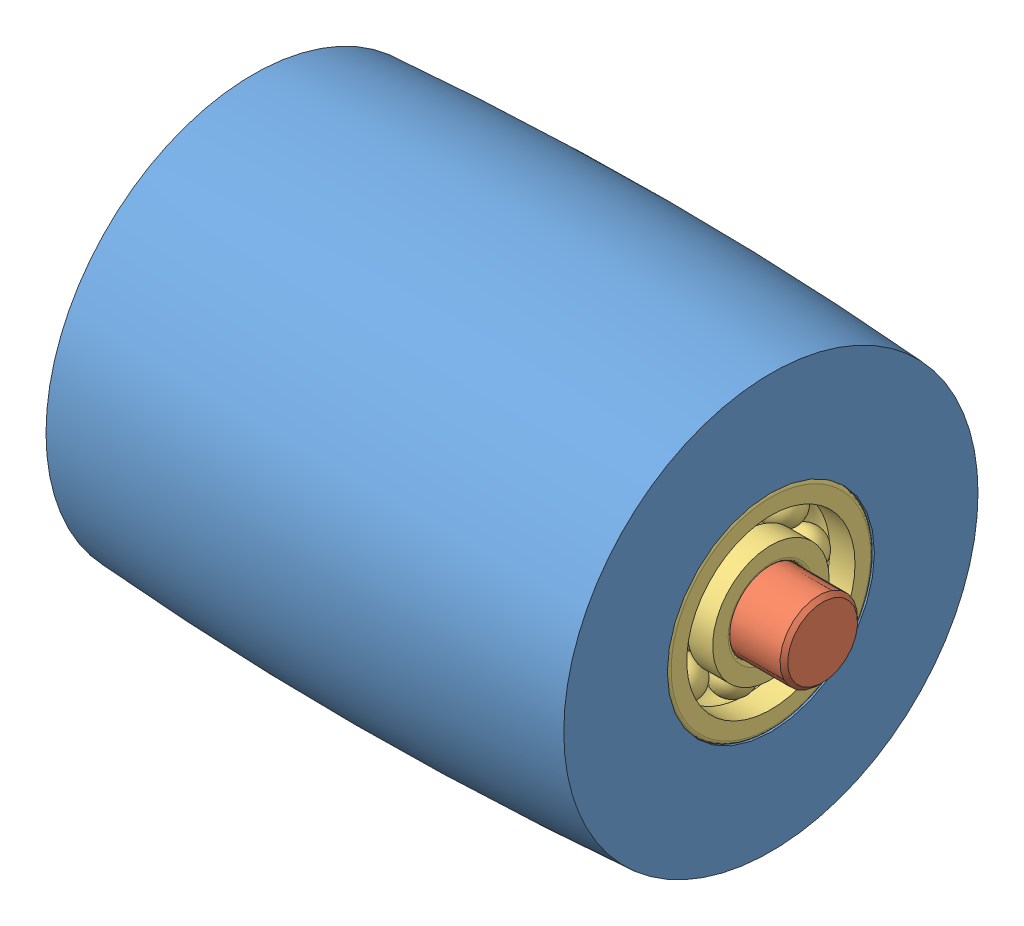
SolidWorks assembly roller assembly, configuration Default. Lengths in mm.
Overall size (24 16.97 16.97).
4 component instances, 3 part files, 7 mates.
Components (placement in the parent):
- omni3-1: omni3 [Default] at (-3.0466 8.2445 17.1115) size (20 16.97 16.97)
- omni4-1: omni4 [Default] at (-5.0466 8.2445 17.1115) x (0 0.996795 -0.079995) z (1 0 0) size (3 3 24)
- instrument ball bearing_68_am-1: instrument ball bearing_68_am [AFBMA 12.1.4.1 - 0030-8 - 8,DE,NC,8_68] at (15.4534 8.2445 17.1115) size (3 8 8)
- instrument ball bearing_68_am-2: instrument ball bearing_68_am [AFBMA 12.1.4.1 - 0030-8 - 8,DE,NC,8_68] at (-1.5466 8.2445 17.1115) size (3 8 8)
Mates (geometry in assembly coordinates):
- Concentric1: concentric aligned: cylinder of omni3-1 through (-3.0466 8.2445 17.1115) axis (-1 0 0) radius 2; cylinder of omni4-1 through (18.9534 8.2445 17.1115) axis (-1 0 0) radius 1.5
- Width1: width aligned: plane of omni4-1 through (18.9534 8.2445 17.1115) normal (1 0 0); plane of omni3-1 through (-5.0466 8.2445 17.1115) normal (-1 0 0); plane of omni4-1 through (16.9534 12.2445 17.1115) normal (1 0 0); plane of omni3-1 through (-3.0466 16.3945 17.1115) normal (-1 0 0)
- Concentric2: concentric anti-aligned: cylinder of omni3-1 through (-3.0466 8.2445 17.1115) axis (-1 0 0) radius 4; cylinder of instrument ball bearing_68_am-1 through (-5.1841 8.2445 17.1115) axis (1 0 0) radius 4
- Coincident1: coincident aligned: plane of omni3-1 through (16.9534 12.2445 17.1115) normal (1 0 0); plane of instrument ball bearing_68_am-1 through (16.9534 12.0945 17.1115) normal (1 0 0)
- Concentric3: concentric anti-aligned: cylinder of omni3-1 through (-3.0466 8.2445 17.1115) axis (-1 0 0) radius 4; cylinder of instrument ball bearing_68_am-2 through (-22.1841 8.2445 17.1115) axis (1 0 0) radius 4
- Coincident2: coincident aligned: plane of omni3-1 through (-3.0466 16.3945 17.1115) normal (-1 0 0); plane of instrument ball bearing_68_am-2 through (-3.0466 10.4945 17.1115) normal (-1 0 0)
- Coincident3: coincident aligned: plane of omni3-1 through (-3.0466 16.3945 17.1115) normal (-1 0 0); plane of instrument ball bearing_68_am-2 through (-3.0466 11.4945 17.1115) normal (-1 0 0)
